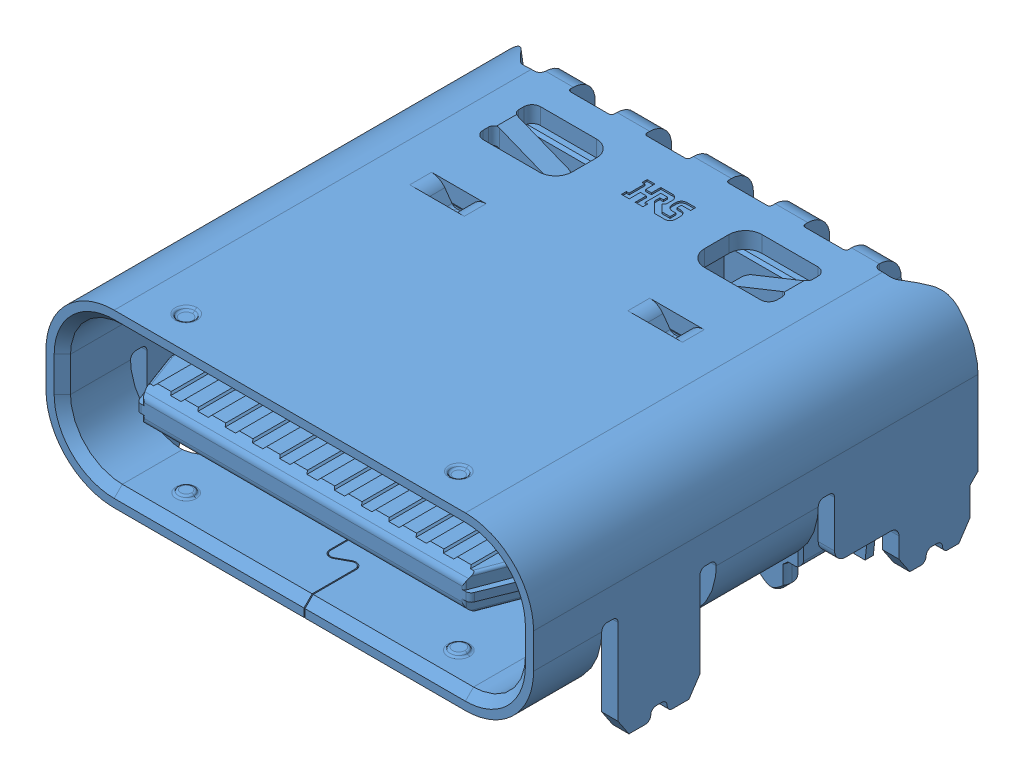
SolidWorks assembly CX90B1-24P_4800497000_3D, configuration Default. Lengths in mm.
Overall size (8.95 3.77 8.17).
2 component instances, 1 part files, 0 mates.
Components (placement in the parent):
- CX90B1-24P_4800497000_3D.stp-1: CX90B1-24P_4800497000_3D.stp [Default] at origin size (8.95 3.77 8.17)
  - CX90B1-24P.stp-1: CX90B1-24P.stp [Default] at (-4.592 -1.505 24.2234) size (8.95 3.77 8.17)
